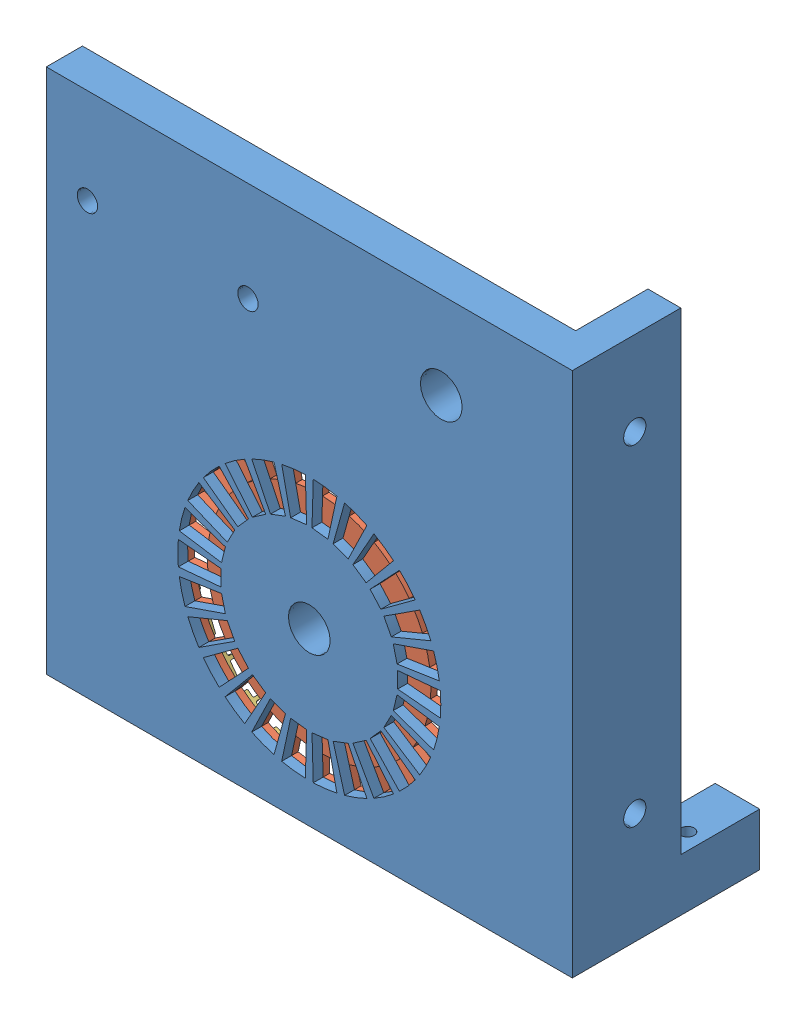
SolidWorks assembly indication panel assembly, configuration Default. Lengths in mm.
Overall size (80 81.5 28.5).
30 component instances, 3 part files, 2 mates.
Components (placement in the parent):
- LED panel-1: LED panel [Default] at (34.0802 38.962 59.6162) size (80 80 28.5)
- indication pcb assembly-1: indication pcb assembly [Default] at (55.4357 -6.4979 102.4788) x (-1 0 0) z (0 0 -1) size (55 56.48 3.5)
  - indication PCB-1: indication PCB [Default] at (21.3555 31.4598 41.8626) size (55 56.48 1)
  - spring pin-1: spring pin [Default] at (43.9085 31.3248 43.6626) x (0.090499 -0.995897 0) z (-0.995897 -0.090499 0) size (3.66 2.5 0.96)
  - spring pin-27: spring pin [Default] at (43.2208 25.9314 43.6626) x (-0.150465 -0.988615 0) z (-0.988615 0.150465 0) size (3.66 2.5 0.96)
  - spring pin-28: spring pin [Default] at (41.2624 20.8593 43.6626) x (-0.382683 -0.92388 0) z (-0.92388 0.382683 0) size (3.66 2.5 0.96)
  - spring pin-29: spring pin [Default] at (38.1471 16.4033 43.6626) x (-0.592662 -0.805451 0) z (-0.805451 0.592662 0) size (3.66 2.5 0.96)
  - spring pin-30: spring pin [Default] at (34.0559 12.8224 43.6626) x (-0.768198 -0.640213 0) z (-0.640213 0.768198 0) size (3.66 2.5 0.96)
  - spring pin-31: spring pin [Default] at (29.2266 10.3245 43.6626) x (-0.899088 -0.437768 0) z (-0.437768 0.899088 0) size (3.66 2.5 0.96)
  - spring pin-32: spring pin [Default] at (23.9398 9.055 43.6626) x (-0.977727 -0.209881 0) z (-0.209881 0.977727 0) size (3.66 2.5 0.96)
  - spring pin-33: spring pin [Default] at (18.5029 9.0876 43.6626) x (-0.999544 0.030203 0) z (0.030203 0.999544 0) size (3.66 2.5 0.96)
  - spring pin-34: spring pin [Default] at (13.2318 10.4204 43.6626) x (-0.963271 0.268532 0) z (0.268532 0.963271 0) size (3.66 2.5 0.96)
  - spring pin-35: spring pin [Default] at (8.4328 12.9759 43.6626) x (-0.871016 0.491255 0) z (0.491255 0.871016 0) size (3.66 2.5 0.96)
  - spring pin-36: spring pin [Default] at (4.3848 16.6056 43.6626) x (-0.728141 0.685427 0) z (0.685427 0.728141 0) size (3.66 2.5 0.96)
  - spring pin-37: spring pin [Default] at (1.323 21.0986 43.6626) x (-0.542949 0.839766 0) z (0.839766 0.542949 0) size (3.66 2.5 0.96)
  - spring pin-38: spring pin [Default] at (-0.5745 26.1937 43.6626) x (-0.326203 0.9453 0) z (0.9453 0.326203 0) size (3.66 2.5 0.96)
  - spring pin-39: spring pin [Default] at (-1.1975 31.5949 43.6626) x (-0.090499 0.995897 0) z (0.995897 0.090499 0) size (3.66 2.5 0.96)
  - spring pin-40: spring pin [Default] at (-0.5098 36.9883 43.6626) x (0.150465 0.988615 0) z (0.988615 -0.150465 0) size (3.66 2.5 0.96)
  - spring pin-41: spring pin [Default] at (1.4486 42.0604 43.6626) x (0.382683 0.92388 0) z (0.92388 -0.382683 0) size (3.66 2.5 0.96)
  - spring pin-42: spring pin [Default] at (4.5639 46.5163 43.6626) x (0.592662 0.805451 0) z (0.805451 -0.592662 0) size (3.66 2.5 0.96)
  - spring pin-43: spring pin [Default] at (8.6551 50.0973 43.6626) x (0.768198 0.640213 0) z (0.640213 -0.768198 0) size (3.66 2.5 0.96)
  - spring pin-44: spring pin [Default] at (13.4844 52.5951 43.6626) x (0.899088 0.437768 0) z (0.437768 -0.899088 0) size (3.66 2.5 0.96)
  - spring pin-45: spring pin [Default] at (18.7711 53.8647 43.6626) x (0.977727 0.209881 0) z (0.209881 -0.977727 0) size (3.66 2.5 0.96)
  - spring pin-46: spring pin [Default] at (24.208 53.8321 43.6626) x (0.999544 -0.030203 0) z (-0.030203 -0.999544 0) size (3.66 2.5 0.96)
  - spring pin-47: spring pin [Default] at (29.4792 52.4993 43.6626) x (0.963271 -0.268532 0) z (-0.268532 -0.963271 0) size (3.66 2.5 0.96)
  - spring pin-48: spring pin [Default] at (34.2782 49.9438 43.6626) x (0.871016 -0.491255 0) z (-0.491255 -0.871016 0) size (3.66 2.5 0.96)
  - spring pin-49: spring pin [Default] at (38.3262 46.3141 43.6626) x (0.728141 -0.685427 0) z (-0.685427 -0.728141 0) size (3.66 2.5 0.96)
  - spring pin-50: spring pin [Default] at (41.3879 41.8211 43.6626) x (0.542949 -0.839766 0) z (-0.839766 -0.542949 0) size (3.66 2.5 0.96)
  - spring pin-51: spring pin [Default] at (43.2854 36.726 43.6626) x (0.326203 -0.9453 0) z (-0.9453 -0.326203 0) size (3.66 2.5 0.96)
  - spring pin-52: spring pin [Default] at (21.7527 46.348 43.6626) x (1 0 0) z (0 -1 0) size (3.66 2.5 0.96)
Mates (geometry in assembly coordinates):
- Coincident3: coincident aligned: circle of LED panel-1; circle of indication pcb assembly-1/indication PCB-1
- Coincident4: coincident anti-aligned: plane of LED panel-1 through (35.0802 52.4438 60.6162) normal (-1 0 0); plane of indication pcb assembly-1/indication PCB-1 through (35.0802 52.4438 59.6162) normal (1 0 0)
